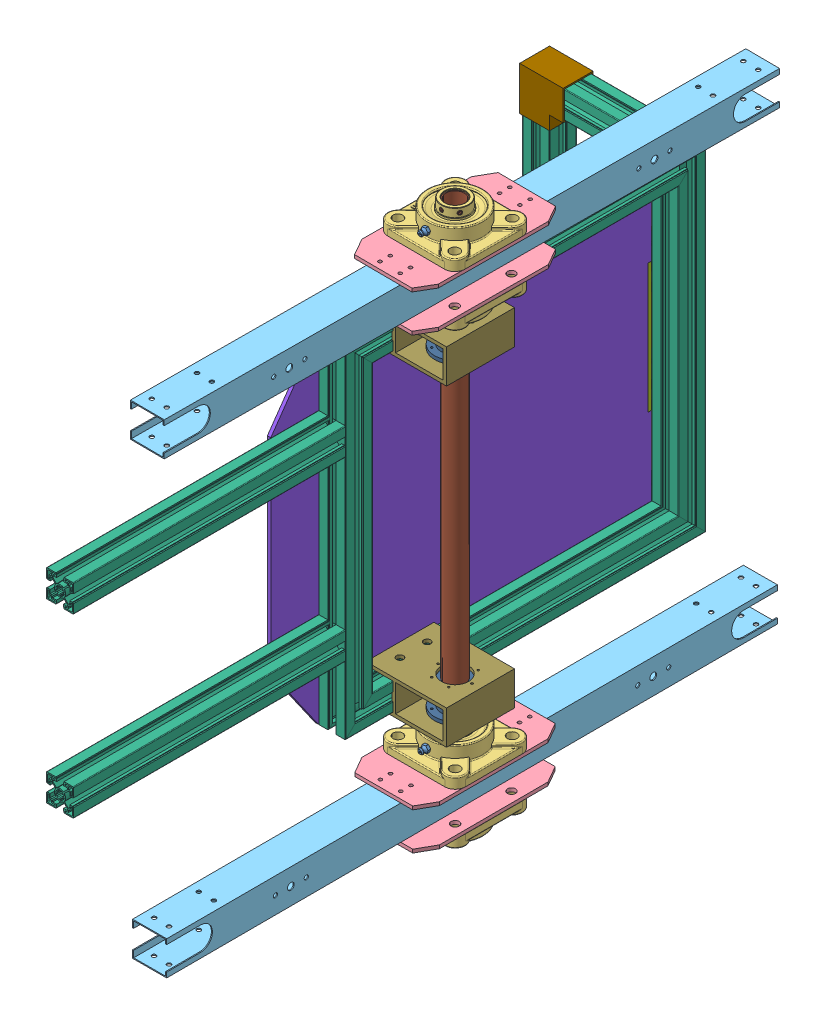
SolidWorks assembly new_rocker_system, configuration Default. Lengths in mm.
Overall size (330.59 804.88 971.09).
46 component instances, 12 part files, 41 mates.
Components (placement in the parent):
- rocker_jointsubsystem-1: rocker_jointsubsystem [Default] at (181.4885 262.5603 220.9917) x (0.00564 0 -0.999984) z (0.999984 0 0.00564) size (210 47.72 114)
  - flange bearing 30mm-1: flange bearing 30mm [Default] at (72.208 -8.45 -23.8516) size (114 42.72 114)
    - 1_4-28 UNF-1: 1_4-28 UNF [Default] at (-91.9125 10.4988 -4.5725) x (0 0.641031 0.767515) z (0 -0.767515 0.641031) size (11.01 16.68 11.01)
    - socket set screw cone point_am(B18.3.6M - M5 x 0.8 x 6 Hex Socket Cone Pt. SS --N)-1: socket set screw cone point_am(B18.3.6M - M5 x 0.8 x 6 Hex Socket Cone Pt. SS --N) [Default] at (-70.2962 25.6188 -4.5725) size (7.2 6 6)
    - UCF205-1: UCF205 [Default] at (-50.462 -8.0431 -4.5766) size (114 42.72 114)
    - socket set screw cone point_am(B18.3.6M - M5 x 0.8 x 6 Hex Socket Cone Pt. SS --N)-2: socket set screw cone point_am(B18.3.6M - M5 x 0.8 x 6 Hex Socket Cone Pt. SS --N) [Default] at (-60.3851 25.6188 12.594) x (0.5 0 -0.866025) z (0.866025 0 0.5) size (7.2 6 6)
  - pilow bearing flange plate-1: pilow bearing flange plate [Default] at (21.734 -23.9512 -29.329) x (1 0 0) z (0 1 0) size (210 113.42 5)
- rocker bar-1: rocker bar [Default] at (50.5915 517.4955 262.4637) x (-0.015257 0 -0.999884) z (0 -1 0) size (900.85 68.8 50)
  - v2joint_2-chassis-rocker-1: v2joint_2-chassis-rocker [Default] at (708.5009 611.8486 671.3885) x (0 0 -1) z (-0.999782 -0.020897 0) size (50 50 900)
    - v2rocker1-1: v2rocker1 [Default] at (367.5021 494.6728 207.1881) size (50 50 900)
- rocker_jointsubsystem-2: rocker_jointsubsystem [Default] at (181.7337 164.658 177.5244) x (-0.00564 0 0.999984) z (0.999984 0 0.00564) size (210 47.72 114)
  - flange bearing 30mm-1: flange bearing 30mm [Default] at (72.208 -8.45 -23.8516) size (114 42.72 114)
    - 1_4-28 UNF-1: 1_4-28 UNF [Default] at (-91.9125 10.4988 -4.5725) x (0 0.641031 0.767515) z (0 -0.767515 0.641031) size (11.01 16.68 11.01)
    - socket set screw cone point_am(B18.3.6M - M5 x 0.8 x 6 Hex Socket Cone Pt. SS --N)-1: socket set screw cone point_am(B18.3.6M - M5 x 0.8 x 6 Hex Socket Cone Pt. SS --N) [Default] at (-70.2962 25.6188 -4.5725) size (7.2 6 6)
    - UCF205-1: UCF205 [Default] at (-50.462 -8.0431 -4.5766) size (114 42.72 114)
    - socket set screw cone point_am(B18.3.6M - M5 x 0.8 x 6 Hex Socket Cone Pt. SS --N)-2: socket set screw cone point_am(B18.3.6M - M5 x 0.8 x 6 Hex Socket Cone Pt. SS --N) [Default] at (-60.3851 25.6188 12.594) x (0.5 0 -0.866025) z (0.866025 0 0.5) size (7.2 6 6)
  - pilow bearing flange plate-1: pilow bearing flange plate [Default] at (21.734 -23.9512 -29.329) x (1 0 0) z (0 1 0) size (210 113.42 5)
- real chasis-1: real chasis [Default] at (1098.0789 -866.5539 -1484.1004) x (0 1 0) z (0 0 1) size (504 232 935)
  - v2V1_chassis_P2(Default_As Machined_)-1-1: v2V1_chassis_P2(Default_As Machined_)-1 [Default] at (750.443 1005.8861 1538.1982) size (500 230 930)
  - chassis plate back-1-1: chassis plate back-1 [Default] at (655.443 1025.8861 1313.1982) size (190 190 5)
  - chassis plate back-1-2: chassis plate back-1 [Default] at (655.443 1025.8861 1268.1982) size (190 190 5)
  - base plate-1-1: base plate-1 [Default] at (500.443 1025.8861 1313.1982) x (0 0 1) z (-1 0 0) size (560 5 500)
  - corner-1-1: corner-1 [Default] at (1002.443 1175.8861 1273.1982) x (0 0 1) z (-1 0 0) size (44 64 64)
  - corner-1-2: corner-1 [Default] at (498.443 1175.8861 1313.1982) x (0 0 -1) z (1 0 0) size (44 64 64)
- axial loacking system-1: axial loacking system [Default] at (153.1874 133.8892 199.0977) x (0.797549 0 0.603254) z (0 -1 0) size (60 60 20)
- axial loacking system-2: axial loacking system [Default] at (153.1874 -366.1108 199.0977) x (0.866025 0 -0.5) z (0 1 0) size (60 60 20)
- pilow bearing flange plate-1: pilow bearing flange plate [Default] at (154.0923 -420.8308 199.096) x (0.001944 0 0.999998) z (0 1 0) size (210 113.42 5)
- flange bearing 30mm-1: flange bearing 30mm [Default] at (157.6618 -405.3296 148.6149) x (-0.001944 0 -0.999998) z (0.999998 0 -0.001944) size (114 42.72 114)
  - 1_4-28 UNF-1: 1_4-28 UNF [Default] at (-91.9125 10.4988 -4.5725) x (0 0.641031 0.767515) z (0 -0.767515 0.641031) size (11.01 16.68 11.01)
  - socket set screw cone point_am(B18.3.6M - M5 x 0.8 x 6 Hex Socket Cone Pt. SS --N)-1: socket set screw cone point_am(B18.3.6M - M5 x 0.8 x 6 Hex Socket Cone Pt. SS --N) [Default] at (-70.2962 25.6188 -4.5725) size (7.2 6 6)
  - UCF205-1: UCF205 [Default] at (-50.462 -8.0431 -4.5766) size (114 42.72 114)
  - socket set screw cone point_am(B18.3.6M - M5 x 0.8 x 6 Hex Socket Cone Pt. SS --N)-2: socket set screw cone point_am(B18.3.6M - M5 x 0.8 x 6 Hex Socket Cone Pt. SS --N) [Default] at (-60.3851 25.6188 12.594) x (0.5 0 -0.866025) z (0.866025 0 0.5) size (7.2 6 6)
- flange bearing 30mm-2: flange bearing 30mm [Default] at (157.858 -486.332 249.5628) x (0.001944 0 0.999998) z (0.999998 0 -0.001944) size (114 42.72 114)
  - 1_4-28 UNF-1: 1_4-28 UNF [Default] at (-91.9125 10.4988 -4.5725) x (0 0.641031 0.767515) z (0 -0.767515 0.641031) size (11.01 16.68 11.01)
  - socket set screw cone point_am(B18.3.6M - M5 x 0.8 x 6 Hex Socket Cone Pt. SS --N)-1: socket set screw cone point_am(B18.3.6M - M5 x 0.8 x 6 Hex Socket Cone Pt. SS --N) [Default] at (-70.2962 25.6188 -4.5725) size (7.2 6 6)
  - UCF205-1: UCF205 [Default] at (-50.462 -8.0431 -4.5766) size (114 42.72 114)
  - socket set screw cone point_am(B18.3.6M - M5 x 0.8 x 6 Hex Socket Cone Pt. SS --N)-2: socket set screw cone point_am(B18.3.6M - M5 x 0.8 x 6 Hex Socket Cone Pt. SS --N) [Default] at (-60.3851 25.6188 12.594) x (0.5 0 -0.866025) z (0.866025 0 0.5) size (7.2 6 6)
- pilow bearing flange plate-2: pilow bearing flange plate [Default] at (154.0923 -475.8308 199.096) x (0.001944 0 0.999998) z (0 1 0) size (210 113.42 5)
- rocker bar-2: rocker bar [Default] at (51.0751 -141.9445 263.24) x (-0.02284 0 -0.999739) z (0 -1 0) size (900.85 68.8 50)
  - v2joint_2-chassis-rocker-1: v2joint_2-chassis-rocker [Default] at (708.5009 611.8486 671.3885) x (0 0 -1) z (-0.999782 -0.020897 0) size (50 50 900)
    - v2rocker1-1: v2rocker1 [Default] at (367.5021 494.6728 207.1881) size (50 50 900)
- internal rod-1: internal rod [Default] at (153.1874 284.4283 199.0977) x (-0.999832 0 0.018343) z (0 -1 0) size (30 30 800)
- internal rod support-1: internal rod support [Default] at (130.6874 -371.1108 199.0977) x (0 0 -1) z (0 1 0) size (100 120 50)
- internal rod support-2: internal rod support [Default] at (130.6874 138.8892 199.0977) x (0 0 1) z (0 -1 0) size (100 120 50)
- axial loacking system-3: axial loacking system [Default] at (153.1874 -326.1108 199.0977) x (0 0 -1) z (0 -1 0) size (60 60 20)
- axial loacking system-4: axial loacking system [Default] at (153.1874 93.8892 199.0977) x (-0.866025 0 -0.5) z (0 1 0) size (60 60 20)
Mates (geometry in assembly coordinates):
- Coincident1: coincident anti-aligned: plane of rocker_jointsubsystem-1/pilow bearing flange plate-1 through (152.2826 238.6092 199.0926) normal (0 -1 0); plane of rocker bar-1/v2joint_2-chassis-rocker-1/v2rocker1-1 through (125.6496 238.6092 648.9496) normal (0 1 0)
- Concentric1: concentric aligned: cylinder of rocker_jointsubsystem-1/flange bearing 30mm-1/UCF205-1 through (153.1874 245.5292 199.0977) axis (0 1 0) radius 15; cylinder of rocker bar-1/v2joint_2-chassis-rocker-1/v2rocker1-1 through (153.1874 179.6092 199.0977) axis (0 1 0) radius 15
- Coincident3: coincident anti-aligned: plane of rocker bar-1/v2joint_2-chassis-rocker-1/v2rocker1-1 through (125.6496 188.6092 648.9496) normal (0 -1 0); plane of rocker_jointsubsystem-2/pilow bearing flange plate-1 through (152.2826 188.6092 199.0926) normal (0 1 0)
- Concentric2: concentric anti-aligned: cylinder of rocker bar-1/v2joint_2-chassis-rocker-1/v2rocker1-1 through (153.1874 179.6092 199.0977) axis (0 1 0) radius 15; cylinder of rocker_jointsubsystem-2/flange bearing 30mm-1/UCF205-1 through (153.1874 181.6892 199.0977) axis (0 -1 0) radius 15
- Coincident4: coincident aligned: plane of rocker_jointsubsystem-1/pilow bearing flange plate-1 through (209.4449 243.6092 279.8007) normal (0.999984 0 0.00564); plane of rocker_jointsubsystem-2/pilow bearing flange plate-1 through (210.3517 183.6092 119.0345) normal (0.999984 0 0.00564)
- Concentric3: concentric aligned: cylinder of rocker_jointsubsystem-1/pilow bearing flange plate-1 through (168.723 243.6092 104.1839) axis (0 -1 0) radius 2.5; cylinder of rocker bar-1/v2joint_2-chassis-rocker-1/v2rocker1-1 through (168.723 238.6092 104.1839) axis (0 -1 0) radius 2.5
- Coincident8: coincident anti-aligned: plane of pilow bearing flange plate-2 through (154.0923 -470.8308 199.096) normal (0 1 0); plane of rocker bar-2/v2joint_2-chassis-rocker-1/v2rocker1-1 through (129.0621 -470.8308 649.1455) normal (0 -1 0)
- Concentric9: concentric anti-aligned: cylinder of pilow bearing flange plate-2 through (153.1874 -470.8308 199.0977) axis (0 -1 0) radius 17.5; cylinder of rocker bar-2/v2joint_2-chassis-rocker-1/v2rocker1-1 through (153.1874 -479.8308 199.0977) axis (0 1 0) radius 15
- Concentric10: concentric aligned: cylinder of pilow bearing flange plate-2 through (138.3429 -470.8308 279.1267) axis (0 -1 0) radius 2.5; cylinder of rocker bar-2/v2joint_2-chassis-rocker-1/v2rocker1-1 through (138.3429 -420.8308 279.1267) axis (0 -1 0) radius 2.5
- Coincident9: coincident anti-aligned: plane of flange bearing 30mm-2/UCF205-1 through (153.1874 -475.8308 199.0977) normal (0 1 0); plane of pilow bearing flange plate-2 through (154.0923 -475.8308 199.096) normal (0 -1 0)
- Concentric11: concentric aligned: cylinder of flange bearing 30mm-2/UCF205-1 through (153.1874 -477.7508 199.0977) axis (0 -1 0) radius 15; cylinder of pilow bearing flange plate-2 through (153.1874 -470.8308 199.0977) axis (0 -1 0) radius 17.5
- Parallel3: parallel aligned: plane of flange bearing 30mm-2/UCF205-1 through (96.1875 -486.5108 199.2085) normal (-0.999998 0 0.001944); plane of pilow bearing flange plate-2 through (96.3194 -470.8308 118.8237) normal (-0.999998 0 0.001944)
- Concentric14: concentric aligned: cylinder of flange bearing 30mm-1/UCF205-1 through (153.1874 -413.9108 199.0977) axis (0 1 0) radius 15; cylinder of rocker bar-2/v2joint_2-chassis-rocker-1/v2rocker1-1 through (153.1874 -479.8308 199.0977) axis (0 1 0) radius 15
- Parallel4: parallel aligned: plane of flange bearing 30mm-1/UCF205-1 through (96.1875 -405.1508 199.2085) normal (-0.999998 0 0.001944); plane of rocker bar-2/v2joint_2-chassis-rocker-1/v2rocker1-1 through (129.0621 -470.8308 649.1455) normal (-0.999998 0 0.001944)
- Coincident13: coincident anti-aligned: plane of pilow bearing flange plate-1 through (154.0923 -420.8308 199.096) normal (0 -1 0); plane of rocker bar-2/v2joint_2-chassis-rocker-1/v2rocker1-1 through (129.0621 -420.8308 649.1455) normal (0 1 0)
- Concentric15: concentric anti-aligned: cylinder of pilow bearing flange plate-1 through (153.1874 -415.8308 199.0977) axis (0 -1 0) radius 17.5; cylinder of rocker bar-2/v2joint_2-chassis-rocker-1/v2rocker1-1 through (153.1874 -479.8308 199.0977) axis (0 1 0) radius 15
- Coincident14: coincident aligned: cylinder of pilow bearing flange plate-1 through (168.0319 -415.8308 119.0687) axis (0 -1 0) radius 2.5; circle of rocker bar-2/v2joint_2-chassis-rocker-1/v2rocker1-1
- Coincident15: coincident anti-aligned: plane of pilow bearing flange plate-1 through (154.0923 -415.8308 199.096) normal (0 1 0); plane of flange bearing 30mm-1/UCF205-1 through (153.1874 -415.8308 199.0977) normal (0 -1 0)
- Concentric17: concentric anti-aligned: cylinder of axial loacking system-2 through (153.1874 -346.1108 199.0977) axis (0 -1 0) radius 20; cylinder of internal rod-1 through (153.1874 -515.5717 199.0977) axis (0 1 0) radius 15
- Concentric18: concentric aligned: cylinder of axial loacking system-1 through (153.1874 113.8892 199.0977) axis (0 1 0) radius 15; cylinder of internal rod-1 through (153.1874 -515.5717 199.0977) axis (0 1 0) radius 15
- Distance1: distance = 7 mm anti-aligned: plane of real chasis-1/v2V1_chassis_P2(Default_As Machined_)-1-1 through (98.1928 133.8892 -190.9023) normal (0 1 0); plane of rocker_jointsubsystem-2/flange bearing 30mm-1/UCF205-1 through (153.1874 140.8892 199.0977) normal (0 -1 0)
- Distance2: distance = 7 mm anti-aligned: plane of flange bearing 30mm-1/UCF205-1 through (153.1874 -373.1108 199.0977) normal (0 1 0); plane of real chasis-1/v2V1_chassis_P2(Default_As Machined_)-1-1 through (98.1928 -366.1108 299.0977) normal (0 -1 0)
- Concentric19: concentric aligned: cylinder of flange bearing 30mm-1/UCF205-1 through (153.1874 -413.9108 199.0977) axis (0 1 0) radius 15; cylinder of internal rod-1 through (153.1874 -515.5717 199.0977) axis (0 1 0) radius 15
- Concentric20: concentric aligned: cylinder of rocker_jointsubsystem-1/flange bearing 30mm-1/UCF205-1 through (153.1874 245.5292 199.0977) axis (0 1 0) radius 15; cylinder of internal rod-1 through (153.1874 -515.5717 199.0977) axis (0 1 0) radius 15
- Coincident16: coincident anti-aligned: plane of real chasis-1/v2V1_chassis_P2(Default_As Machined_)-1-1 through (73.1928 -366.1108 299.0977) normal (0 -1 0); plane of internal rod support-1 through (130.6874 -366.1108 199.0977) normal (0 1 0)
- Coincident17: coincident anti-aligned: plane of axial loacking system-2 through (153.1874 -366.1108 199.0977) normal (0 -1 0); plane of internal rod support-1 through (130.6874 -366.1108 199.0977) normal (0 1 0)
- Coincident19: coincident anti-aligned: plane of real chasis-1/v2V1_chassis_P2(Default_As Machined_)-1-1 through (111.1928 93.8892 -190.9023) normal (0 -1 0); plane of internal rod support-2 through (170.6874 93.8892 149.0977) normal (0 1 0)
- Coincident20: coincident anti-aligned: plane of axial loacking system-1 through (153.1874 133.8892 199.0977) normal (0 1 0); plane of internal rod support-2 through (130.6874 133.8892 199.0977) normal (0 -1 0)
- Concentric21: concentric aligned: cylinder of internal rod-1 through (153.1874 -515.5717 199.0977) axis (0 1 0) radius 15; cylinder of internal rod support-1 through (153.1874 -371.1108 199.0977) axis (0 1 0) radius 20.05
- Concentric22: concentric anti-aligned: cylinder of internal rod-1 through (153.1874 -515.5717 199.0977) axis (0 1 0) radius 15; cylinder of internal rod support-2 through (153.1874 138.8892 199.0977) axis (0 -1 0) radius 20.05
- Concentric23: concentric aligned: cylinder of real chasis-1/v2V1_chassis_P2(Default_As Machined_)-1-1 through (92.1928 -366.1108 219.0977) axis (0 1 0) radius 5; cylinder of internal rod support-1 through (92.1928 -371.1108 219.0977) axis (0 1 0) radius 5.1
- Concentric24: concentric aligned: cylinder of real chasis-1/v2V1_chassis_P2(Default_As Machined_)-1-1 through (92.1928 -366.1108 179.0977) axis (0 1 0) radius 5; cylinder of internal rod support-1 through (92.1928 -371.1108 179.0977) axis (0 1 0) radius 5.1
- Concentric25: concentric anti-aligned: cylinder of real chasis-1/v2V1_chassis_P2(Default_As Machined_)-1-1 through (92.1928 -366.1108 219.0977) axis (0 1 0) radius 5; cylinder of internal rod support-2 through (92.1928 138.8892 219.0977) axis (0 -1 0) radius 5.1
- Concentric26: concentric anti-aligned: cylinder of real chasis-1/v2V1_chassis_P2(Default_As Machined_)-1-1 through (92.1928 -366.1108 179.0977) axis (0 1 0) radius 5; cylinder of internal rod support-2 through (92.1928 138.8892 179.0977) axis (0 -1 0) radius 5.1
- Coincident21: coincident anti-aligned: plane of internal rod support-1 through (170.6874 -326.1108 249.0977) normal (0 -1 0); plane of axial loacking system-3 through (153.1874 -326.1108 199.0977) normal (0 1 0)
- Concentric27: concentric aligned: cylinder of internal rod-1 through (153.1874 -515.5717 199.0977) axis (0 1 0) radius 15; cylinder of axial loacking system-3 through (153.1874 -346.1108 199.0977) axis (0 1 0) radius 15
- Concentric28: concentric anti-aligned: cylinder of internal rod support-1 through (128.1874 -371.1108 199.0977) axis (0 1 0) radius 1.5; cylinder of axial loacking system-3 through (128.1874 -321.1108 199.0977) axis (0 -1 0) radius 1.55
- Concentric29: concentric aligned: cylinder of axial loacking system-2 through (128.1874 -371.1108 199.0977) axis (0 1 0) radius 1.55; cylinder of internal rod support-1 through (128.1874 -371.1108 199.0977) axis (0 1 0) radius 1.5
- Concentric30: concentric anti-aligned: cylinder of internal rod-1 through (153.1874 -515.5717 199.0977) axis (0 1 0) radius 15; cylinder of axial loacking system-4 through (153.1874 113.8892 199.0977) axis (0 -1 0) radius 15
- Coincident22: coincident anti-aligned: plane of internal rod support-2 through (170.6874 93.8892 149.0977) normal (0 1 0); plane of axial loacking system-4 through (153.1874 93.8892 199.0977) normal (0 -1 0)
- Concentric31: concentric anti-aligned: cylinder of internal rod support-2 through (140.6874 138.8892 220.7484) axis (0 -1 0) radius 1.5; cylinder of axial loacking system-4 through (140.6874 88.8892 220.7484) axis (0 1 0) radius 1.55
